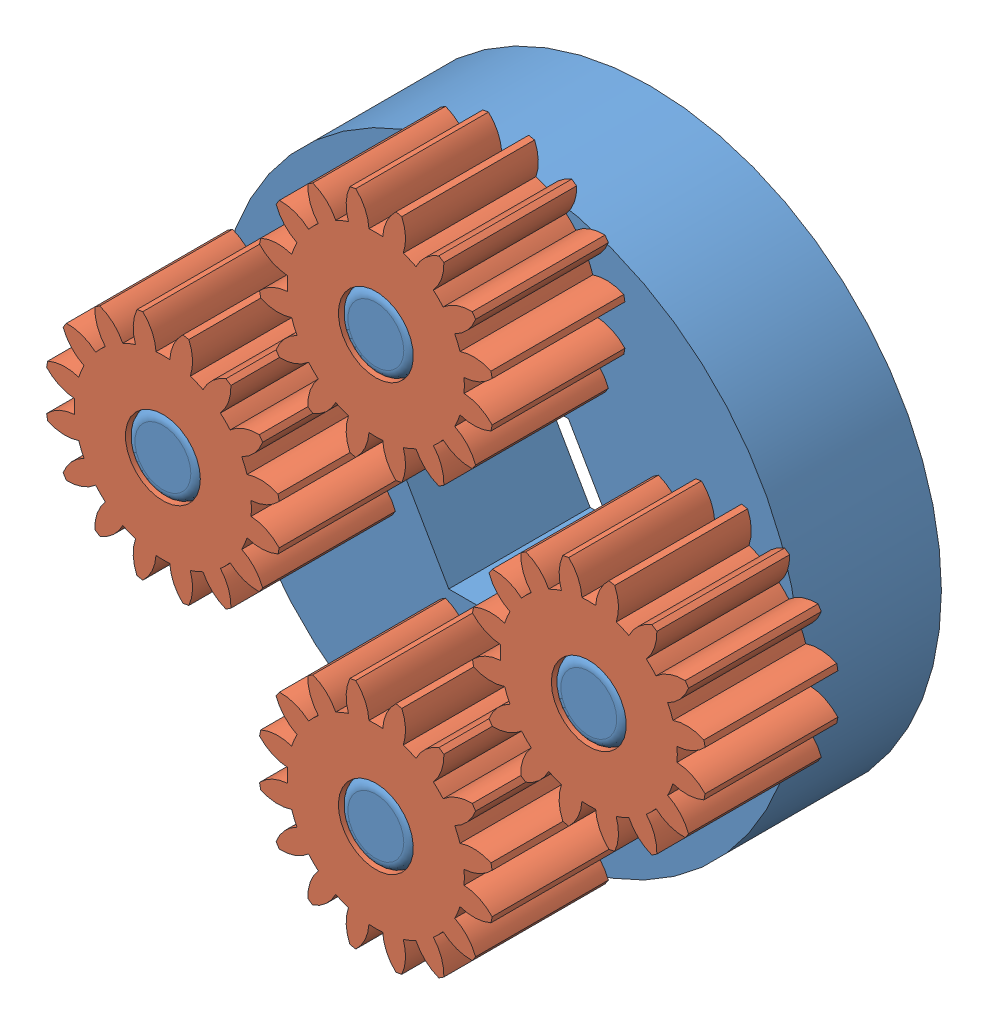
SolidWorks assembly am-XXXX - 4_1 Input Stage, configuration Default. Lengths in mm.
Overall size (35.15 35.15 14.63).
5 component instances, 2 part files, 0 mates.
Components (placement in the parent):
- am-XXXX - 57 Sport Shaft Carrier Plate-1: am-XXXX - 57 Sport Shaft Carrier Plate [Default] at origin size (31.12 31.12 14.63)
- 16T Planet Gear-1: 16T Planet Gear [Default] at (-11.8222 1.3023 11.8494) x (0 0 -1) z (1 0 0) size (7.09 12.42 12.42)
- 16T Planet Gear-2: 16T Planet Gear [Default] at (1.3023 11.8222 11.8494) x (0 0 -1) z (0 -1 0) size (7.09 12.42 12.42)
- 16T Planet Gear-3: 16T Planet Gear [Default] at (11.8222 -1.3023 11.8494) x (0 0 -1) z (-1 0 0) size (7.09 12.42 12.42)
- 16T Planet Gear-4: 16T Planet Gear [Default] at (-1.3023 -11.8222 11.8494) x (0 0 -1) z (0 1 0) size (7.09 12.42 12.42)
